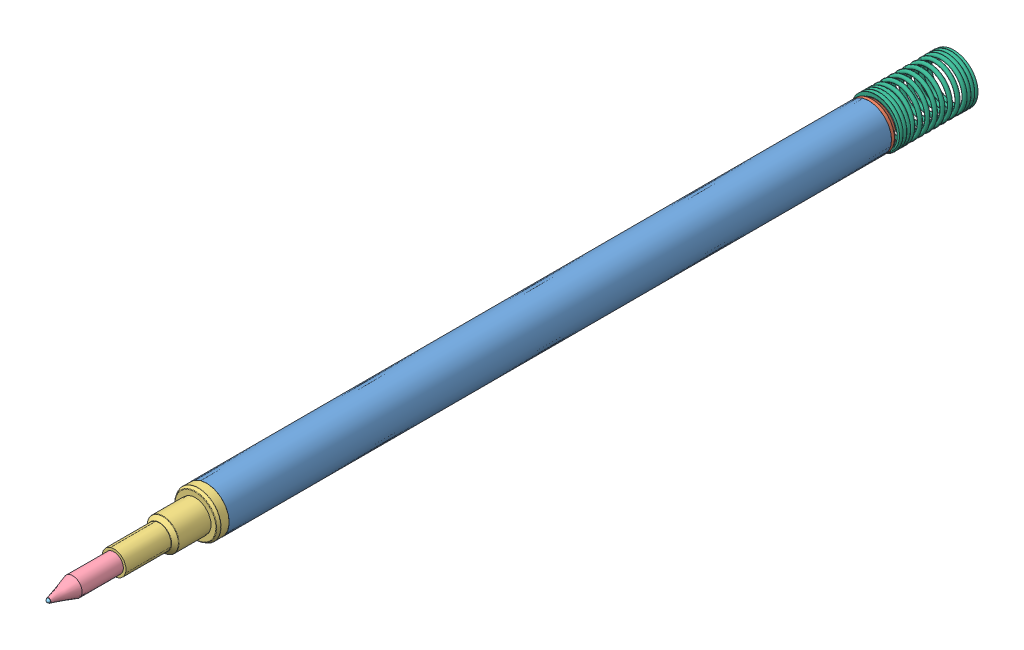
SolidWorks assembly Assembly Ink Cartridge Pilot G2, configuration Default. Lengths in mm.
Overall size (8.33 8.33 120.93).
6 component instances, 6 part files, 14 mates.
Components (placement in the parent):
- Ink Container Tube-2: Ink Container Tube [Default] at (23.3837 43.9569 29.8776) x (-1 0 0) z (0 1 0) size (6.2 88 6)
- Ink Container Back Plug-1: Ink Container Back Plug [Default] at (23.3837 43.9569 29.8776) x (1 0 0) z (0 1 0) size (6 4.9 6)
- Pen Tip Holder-1: Pen Tip Holder [Default] at (23.3837 43.9569 117.8776) x (0.558829 -0.829283 0) z (0.829283 0.558829 0) size (6 18.11 6)
- Pen Tip-1: Pen Tip [Default] at (23.3837 43.9569 135.6644) x (0.943336 0.33184 0) z (-0.33184 0.943336 0) size (2.59 15.69 2.63)
- Roller Ball-2: Roller Ball [Default] at (23.3837 43.9569 138.8644) x (0.307657 -0.299861 -0.903012) z (0.951494 0.099481 0.29114) size (0.5 0.5 0.5)
- Spring-3: Spring [Write] at (23.3837 43.9569 20.2276) x (1 0 0) z (0 -1 0) size (7.26 11.16 7.26)
Mates (geometry in assembly coordinates):
- Concentric1: concentric anti-aligned: circle of Ink Container Tube-2; cylinder of Ink Container Back Plug-1 through (23.3837 43.9569 33.8776) axis (0 0 -1) radius 2.1
- Tangent1: tangent aligned: cylinder of Ink Container Tube-2 through (23.3837 43.9569 117.8776) axis (0 0 -1) radius 2.25; torus of Ink Container Back Plug-1
- Coincident1: coincident anti-aligned: plane of Ink Container Tube-2 through (23.3837 43.9569 29.8776) normal (0 0 -1); plane of Ink Container Back Plug-1 through (23.3837 43.9569 29.8776) normal (0 0 1)
- Concentric2: concentric anti-aligned: cylinder of Ink Container Tube-2 through (23.3837 43.9569 117.8776) axis (0 0 -1) radius 2.25; cylinder of Pen Tip Holder-1 through (23.3837 43.9569 112.8776) axis (0 0 1) radius 2.25
- Coincident2: coincident anti-aligned: plane of Ink Container Tube-2 through (23.3837 43.9569 117.8776) normal (0 0 1); plane of Pen Tip Holder-1 through (23.3837 43.9569 117.8776) normal (0 0 -1)
- Concentric3: concentric aligned: cylinder of Pen Tip Holder-1 through (23.3837 43.9569 120.1159) axis (0 0 1) radius 1.2446; cylinder of Pen Tip-1 through (23.3837 43.9569 123.1744) axis (0 0 1) radius 1.2446
- Concentric4: concentric: cylinder of Pen Tip-1 through (23.3837 43.9569 132.3744) axis (0 0 1) radius 0.25; sphere of Roller Ball-2
- Tangent5: tangent: circle of Pen Tip-1; sphere of Roller Ball-2
- Distance1: distance = 8.6868 mm aligned: plane of Pen Tip-1 through (23.3837 43.9569 138.8644) normal (0 0 1); plane of Pen Tip Holder-1 through (23.3837 43.9569 130.1776) normal (0 0 1)
- Parallel4: parallel aligned: plane of Ink Container Back Plug-1 through (23.3837 43.9569 29.8776) normal (0 1 0)
- Coincident5: coincident anti-aligned: plane of Ink Container Back Plug-1 through (23.3837 43.9569 28.9776) normal (0 0 -1); plane of Spring-3 through (23.3837 43.9569 28.9776) normal (0 0 1)
- Concentric5: concentric: cylinder of Ink Container Tube-2 through (23.3837 43.9569 117.8776) axis (0 0 -1) radius 3; point of Spring-3
- Concentric6: concentric: cylinder of Ink Container Tube-2 through (23.3837 43.9569 117.8776) axis (0 0 -1) radius 3; point of Spring-3
- Parallel5: parallel anti-aligned: plane of Spring-3 through (23.3837 43.9569 20.2276) normal (0 -1 0)
